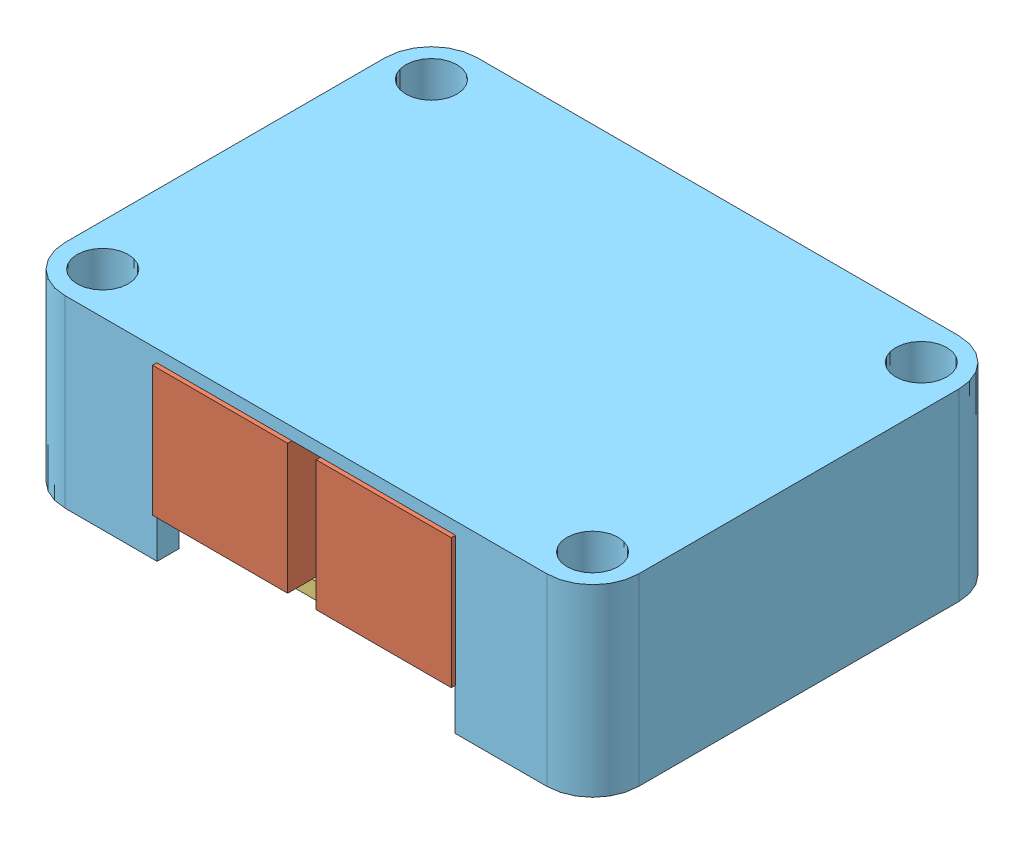
SolidWorks assembly Assembly, configuration Default. Lengths in mm.
Overall size (56.1 24.22 40.69).
12 component instances, 5 part files, 4 mates.
Components (placement in the parent):
- IO-Base-PCB-Mouser-Assembly-1: IO-Base-PCB-Mouser-Assembly [Default] at origin size (51.6 23.02 40.49)
  - IO-Base-PCB-Mouser-1: IO-Base-PCB-Mouser [Default] x (1 0 0) z (0 -1 0) size (51.6 40.49 17.83)
    - IO-Base-Mouser.STEP-1: IO-Base-Mouser.STEP [Default] at origin size (51.6 40.49 17.83)
      - SS-90000-001.STEP-1: SS-90000-001.STEP [Default] at (13.5 -18.5 -0.05) x (-1 0 0) z (0 0 -1) size (15.24 18.26 17.83)
        - COMPOUND.STEP-1: COMPOUND.STEP [Default] at origin size (15.24 18.26 17.83)
      - SS-90000-003.STEP-1: SS-90000-003.STEP [Default] at (8.83 -9.122 -0.05) x (1 0 0) z (0 0 -1) size (13.21 18.1 17.8)
        - COMPOUND-0.STEP-1: COMPOUND-0.STEP [Default] at origin size (13.21 18.1 17.8)
      - SS-90000-003.STEP-2: SS-90000-003.STEP [Default] at (24.83 -9.122 -0.05) x (1 0 0) z (0 0 -1) size (13.21 18.1 17.8)
        - COMPOUND-0.STEP-1: COMPOUND-0.STEP [Default] at origin size (13.21 18.1 17.8)
      - IO-Base-mouser PCB.STEP-1: IO-Base-mouser PCB.STEP [Default] at origin size (51.6 36 1.6)
  - PinHeader_2x08_P2.54mm_Vertical-1: PinHeader_2x08_P2.54mm_Vertical [Default] at (20.22 -1.6 -28.4) x (0 0 1) z (0 -1 0) size (5.08 20.32 11.54)
- case-1: case [Default] at (20 12.08 -12.9) x (-1 0 0) z (0 0 1) size (56.1 18 40.3)
Mates (geometry in assembly coordinates):
- Coincident1: coincident anti-aligned: plane of IO-Base-PCB-Mouser-Assembly-1/IO-Base-PCB-Mouser-1/IO-Base-Mouser.STEP-1/SS-90000-001.STEP-1/COMPOUND.STEP-1 through (9.055 12.88 -23.72) normal (0 1 0); plane of case-1 through (0.9 12.88 -16.25) normal (0 -1 0)
- Parallel1: parallel aligned: line of IO-Base-PCB-Mouser-Assembly-1/IO-Base-PCB-Mouser-1/IO-Base-Mouser.STEP-1/IO-Base-mouser PCB.STEP-1 through (0 -1.6 -30.9) axis (1 0 0); line of case-1 through (16.2 -3.92 -33.05) axis (1 0 0)
- Coincident13: coincident anti-aligned: plane of IO-Base-PCB-Mouser-Assembly-1/IO-Base-PCB-Mouser-1/IO-Base-Mouser.STEP-1/IO-Base-mouser PCB.STEP-1 through (40 0 0) normal (1 0 0); plane of case-1 through (40 -3.92 5.1) normal (-1 0 0)
- Coincident12: coincident anti-aligned: plane of IO-Base-PCB-Mouser-Assembly-1/IO-Base-PCB-Mouser-1/IO-Base-Mouser.STEP-1/IO-Base-mouser PCB.STEP-1 through (0 0 -30.9) normal (0 0 -1); plane of case-1 through (39.75 -3.92 -30.9) normal (0 0 1)
